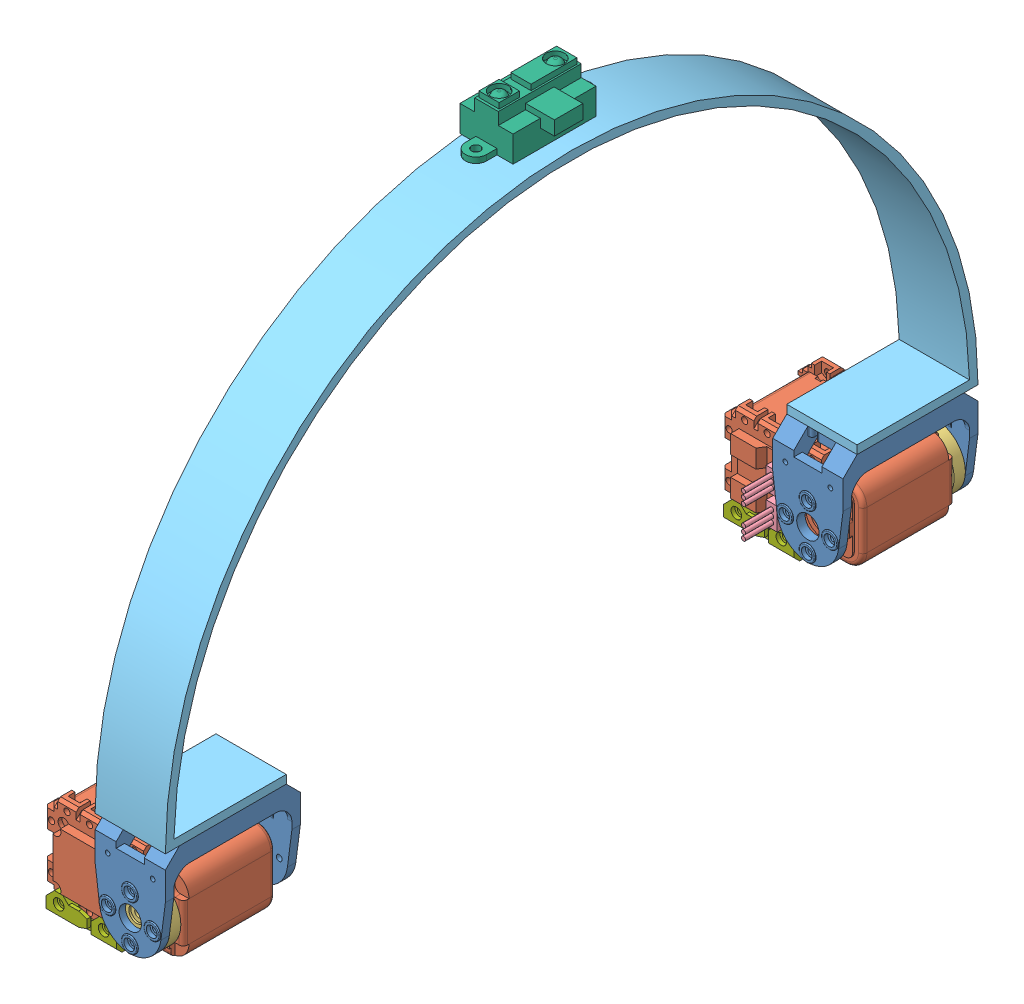
SolidWorks assembly Outil arceau, configuration Défaut. Lengths in mm.
Overall size (52.31 205.1 289.81).
16 component instances, 7 part files, 15 mates.
Components (placement in the parent):
- F2-1: F2 [Défaut] at (74.4439 19.0039 -319.5983) x (0 0 1) z (0 1 0) size (48.81 25 37)
- servomoteur_ax-12-1: servomoteur_ax-12 [Default] at (52.567 16.3271 -315.2958) x (0 -1 0) z (0 0 1) size (32 52.31 53.4)
  - AX-12_modif-1: AX-12_modif [Défaut] at (-2.6768 21.8769 -4.3025) size (32 50.06 38.01)
  - attache_ax-12-1: attache_ax-12 [Default] at (-2.6768 21.8769 12.6975) x (-0.301968 0.953318 0) z (0 0 1) size (22 22 4.7)
  - connecteur_AX-12-1: connecteur_AX-12 [Default] at (6.5732 8.6769 -17.5025) x (-1 0 0) z (0 -1 0) size (8 18.5 4)
  - connecteur_AX-12-2: connecteur_AX-12 [Default] at (-4.0768 8.6769 -17.5025) x (-1 0 0) z (0 -1 0) size (8 18.5 4)
- Arceau-1: Arceau [Défaut] at (86.9439 45.0039 -584.5983) x (0 0 1) z (-1 0 0) size (289 144.5 25)
- GP2D12-1: GP2D12 [Default] at (80.8439 189.5039 -425.3483) x (0 0 -1) z (1 0 0) size (44.5 15.6 23.9)
- F3-1: F3 [Défaut] at (51.9938 0 -319.5983) size (25 9 38)
- F3-2: F3 [Défaut] at (51.9938 0 -560.5983) size (25 9 38)
- servomoteur_ax-12-2: servomoteur_ax-12 [Default] at (52.567 21.6824 -564.9009) x (0 1 0) z (0 0 -1) size (32 52.31 53.4)
  - AX-12_modif-1: AX-12_modif [Défaut] at (-2.6768 21.8769 -4.3025) size (32 50.06 38.01)
  - attache_ax-12-1: attache_ax-12 [Default] at (-2.6768 21.8769 12.6975) x (-0.301968 0.953318 0) z (0 0 1) size (22 22 4.7)
  - connecteur_AX-12-1: connecteur_AX-12 [Default] at (6.5732 8.6769 -17.5025) x (-1 0 0) z (0 -1 0) size (8 18.5 4)
  - connecteur_AX-12-2: connecteur_AX-12 [Default] at (-4.0768 8.6769 -17.5025) x (-1 0 0) z (0 -1 0) size (8 18.5 4)
- F2-2: F2 [Défaut] at (74.4439 19.0039 -560.599) x (0 0 1) z (0 1 0) size (48.81 25 37)
Mates (geometry in assembly coordinates):
- Coaxiale3: concentric aligned: cylinder of servomoteur_ax-12-1/attache_ax-12-1 through (74.4439 19.0039 -302.5993) axis (0 0 1) radius 1.4; cylinder of F2-1 through (74.4439 19.0039 -295.5983) axis (0 0 1) radius 4
- Coïncidente63: coincident anti-aligned: plane of servomoteur_ax-12-1/attache_ax-12-1 through (74.4439 19.0039 -298.5983) normal (0 0 1); plane of F2-1 through (74.4439 19.0039 -298.5983) normal (0 0 -1)
- Orientation arceau: planar angle = 4.712389 rad aligned: plane of F2-1 through (86.9439 30.0039 -343.5983) normal (1 0 0); plane of servomoteur_ax-12-1/AX-12_modif-1 through (80.7339 32.0039 -334.6783) normal (0 1 0)
- Coïncidente69: coincident anti-aligned: plane of F2-1 through (86.9439 45.0039 -343.5983) normal (0 1 0); plane of Arceau-1 through (61.9439 45.0039 -295.5983) normal (0 -1 0)
- Tangent4: tangent aligned: plane of F2-1 through (74.4439 19.0039 -295.5983) normal (0 0 1); cylinder of Arceau-1 through (61.9439 45.0039 -440.0983) axis (1 0 0) radius 144.5
- Coïncidente70: coincident aligned: plane of F2-1 through (86.9439 30.0039 -343.5983) normal (1 0 0); plane of Arceau-1 through (86.9439 45.0039 -440.0983) normal (1 0 0)
- Coïncidente102: coincident anti-aligned: plane of servomoteur_ax-12-1/AX-12_modif-1 through (36.0639 34.6039 -303.5983) normal (0 0 1); plane of F3-1 through (64.4938 3 -303.5983) normal (0 0 -1)
- Tangent13: tangent: face of servomoteur_ax-12-1/AX-12_modif-1; cylinder of F3-1 through (59.9938 5.5 -300.5983) axis (0 0 1) radius 1.05
- Tangent14: tangent: face of servomoteur_ax-12-1/AX-12_modif-1; cylinder of F3-1 through (43.9938 5.5 -300.5983) axis (0 0 1) radius 1.05
- Coïncidente75: coincident aligned: plane of Arceau-1 through (61.9439 45.0039 -440.0983) normal (-1 0 0); plane of GP2D12-1 through (61.9439 198.8039 -425.3483) normal (-1 0 0)
- Coïncidente78: coincident: moEndPointRef_w of Arceau-1; moEndPointRef_w of GP2D12-1
- Tangent6: tangent anti-aligned: cylinder of Arceau-1 through (61.9439 45.0039 -440.0983) axis (1 0 0) radius 144.5; plane of GP2D12-1 through (61.9439 189.5039 -425.3483) normal (0 -1 0)
- Pivot1: hinge anti-aligned: cylinder of servomoteur_ax-12-1/attache_ax-12-1 through (74.4439 19.0039 -302.5993) axis (0 0 1) radius 1.4; cylinder of F2-1 through (74.4439 19.0039 -295.5983) axis (0 0 1) radius 4; plane of servomoteur_ax-12-1/attache_ax-12-1 through (74.4439 19.0039 -298.5983) normal (0 0 1); plane of F2-1 through (74.4439 19.0039 -298.5983) normal (0 0 -1)
- Coïncidente103: coincident anti-aligned: plane of F3-1 through (51.9938 0 -319.5983) normal (0 -1 0); plane of assembly through (0 0 0) normal (0 1 0)
- PLAN1: unknown: plane of Arceau-1 through (61.9439 45.0039 -584.5983) normal (0 -1 0); unknown of Arceau-1; plane of Arceau-1 through (86.9439 45.0039 -440.0983) normal (1 0 0)
